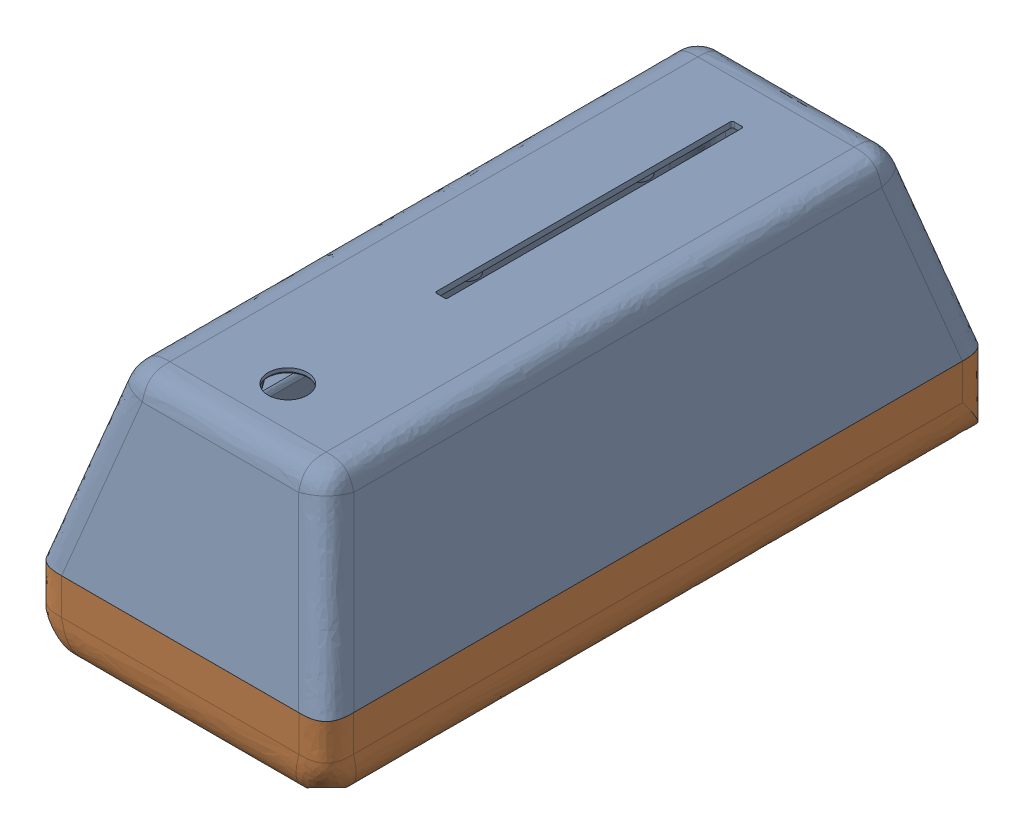
SolidWorks assembly Mini_Light, configuration Default. Lengths in mm.
Overall size (65.43 56.37 147.98).
2 component instances, 2 part files, 3 mates.
Components (placement in the parent):
- Mini_Light_Case-1: Mini_Light_Case [Default] at origin size (65.43 39.26 147.98)
- Base-2: Base [Default] at (-10.2089 -43.1 10.2111) size (64.97 28.65 147.52)
Mates (geometry in assembly coordinates):
- Coincident1: coincident anti-aligned: plane of Mini_Light_Case-1 through (0 -38.1 0) normal (0 -1 0); plane of Base-2 through (-10.2089 -38.1 10.2111) normal (0 1 0)
- Coincident2: coincident: line of Mini_Light_Case-1 through (-10.2089 -38.1 -131.0752) axis (0 0 1); plane of Base-2 through (-10.2089 -56.1 10.2111) normal (-1 0 0)
- Coincident3: coincident aligned: line of Mini_Light_Case-1 through (9.725 -38.1 -137.2089) axis (-1 0 0); line of Base-2 through (48.6111 -38.1 -137.2089) axis (-1 0 0)
